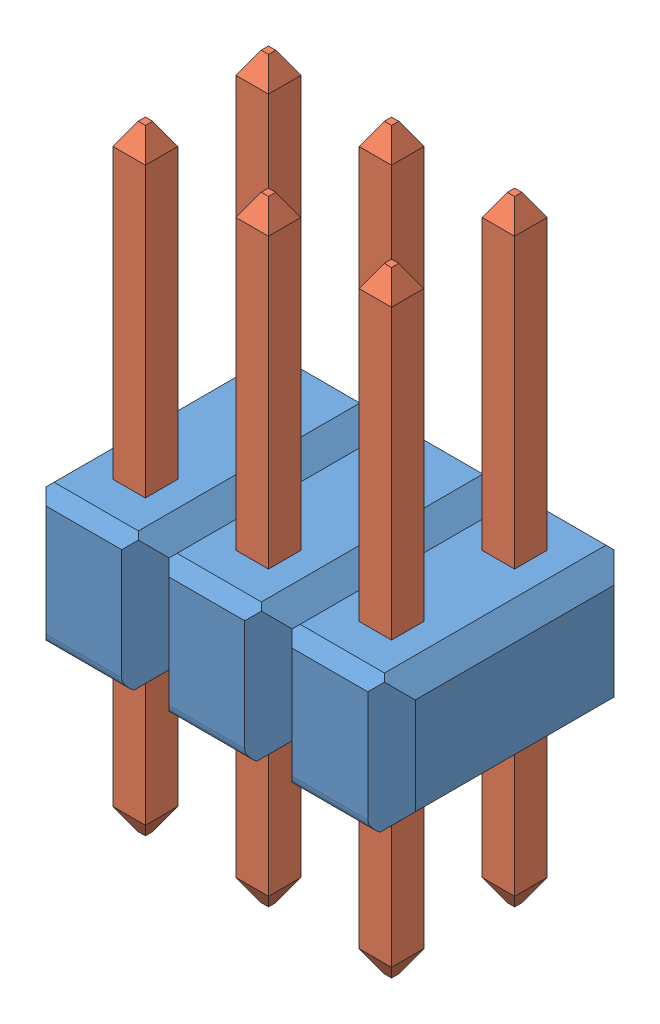
SolidWorks assembly User Library-2x3 TH Pitch 2_54mm, configuration Default. Lengths in mm.
Overall size (7.62 12.7 5.08).
7 component instances, 2 part files, 0 mates.
Components (placement in the parent):
- User Library-2x3 TH Pitch 2_54mm_header2x3-1: User Library-2x3 TH Pitch 2_54mm_header2x3 [Default] at (0 1.4 0) size (7.62 2.8 5.08)
- User Library-2x3 TH Pitch 2_54mm_pin-1: User Library-2x3 TH Pitch 2_54mm_pin [Default] at (1.29 -3.5 1.29) size (0.67 12.7 0.67)
- User Library-2x3 TH Pitch 2_54mm_pin-2: User Library-2x3 TH Pitch 2_54mm_pin [Default] at (1.29 -3.5 -1.25) size (0.67 12.7 0.67)
- User Library-2x3 TH Pitch 2_54mm_pin-3: User Library-2x3 TH Pitch 2_54mm_pin [Default] at (3.83 -3.5 1.29) size (0.67 12.7 0.67)
- User Library-2x3 TH Pitch 2_54mm_pin-4: User Library-2x3 TH Pitch 2_54mm_pin [Default] at (3.83 -3.5 -1.25) size (0.67 12.7 0.67)
- User Library-2x3 TH Pitch 2_54mm_pin-5: User Library-2x3 TH Pitch 2_54mm_pin [Default] at (6.37 -3.5 1.29) size (0.67 12.7 0.67)
- User Library-2x3 TH Pitch 2_54mm_pin-6: User Library-2x3 TH Pitch 2_54mm_pin [Default] at (6.37 -3.5 -1.25) size (0.67 12.7 0.67)
